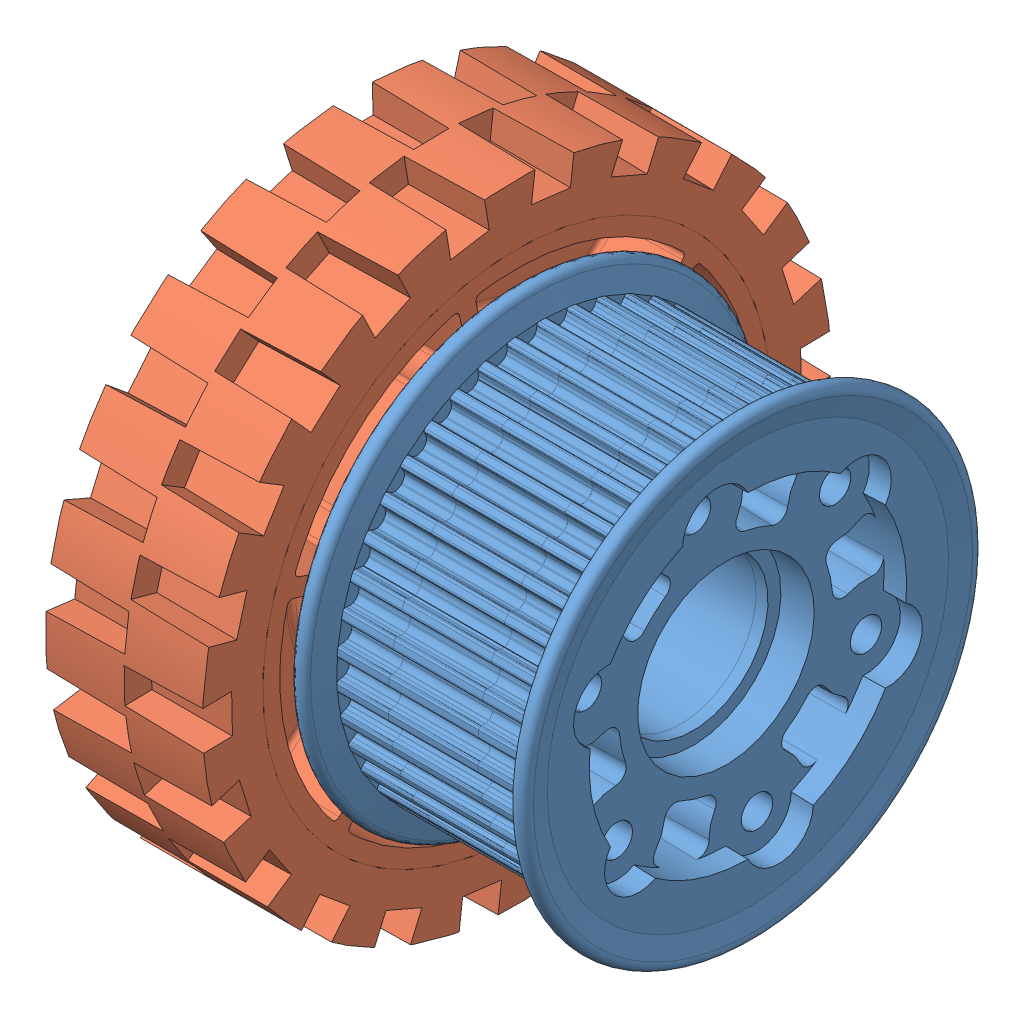
SolidWorks assembly Wheel_Pulley_Asm, configuration Default. Lengths in mm.
Overall size (68.56 143.51 143.51).
2 component instances, 2 part files, 6 mates.
Components (placement in the parent):
- Pulley_HTD5_42_Double_Wide-1: Pulley_HTD5_42_Double_Wide [Default] at (-28.3772 -65.7313 -13.105) x (1 0 0) z (0 0.74145 0.671008) size (37.95 74.23 74.23)
- 4 in HiGrip Wheel-1: 4 in HiGrip Wheel [Default] at (-7.4909 -3.6296 0.1711) x (1 0 0) z (0 0.741478 0.670977) size (35.12 101.6 101.6)
Mates (geometry in assembly coordinates):
- Concentric1: concentric anti-aligned: cylinder of Pulley_HTD5_42_Double_Wide-1 through (9.2351 7.2449 22.6656) axis (-1 0 0) radius 2.54; cylinder of 4 in HiGrip Wheel-1 through (-33.0051 7.2449 22.6656) axis (1 0 0) radius 2.159
- Concentric2: concentric anti-aligned: cylinder of Pulley_HTD5_42_Double_Wide-1 through (9.2351 -7.3593 -22.6649) axis (-1 0 0) radius 2.54; cylinder of 4 in HiGrip Wheel-1 through (-33.0051 -7.3593 -22.6649) axis (1 0 0) radius 2.159
- Coincident1: coincident anti-aligned: plane of Pulley_HTD5_42_Double_Wide-1 through (1.9199 -0.0579 -0.0003) normal (-1 0 0); plane of 4 in HiGrip Wheel-1 through (1.9199 -0.0572 0.0004) normal (1 0 0)
- Coincident2: coincident anti-aligned: circle of Pulley_HTD5_42_Double_Wide-1; plane of assembly through (0 0 0) normal (1 0 0)
- Coincident8: coincident: point of Pulley_HTD5_42_Double_Wide-1; plane of assembly
- Coincident9: coincident: point of Pulley_HTD5_42_Double_Wide-1; plane of assembly
